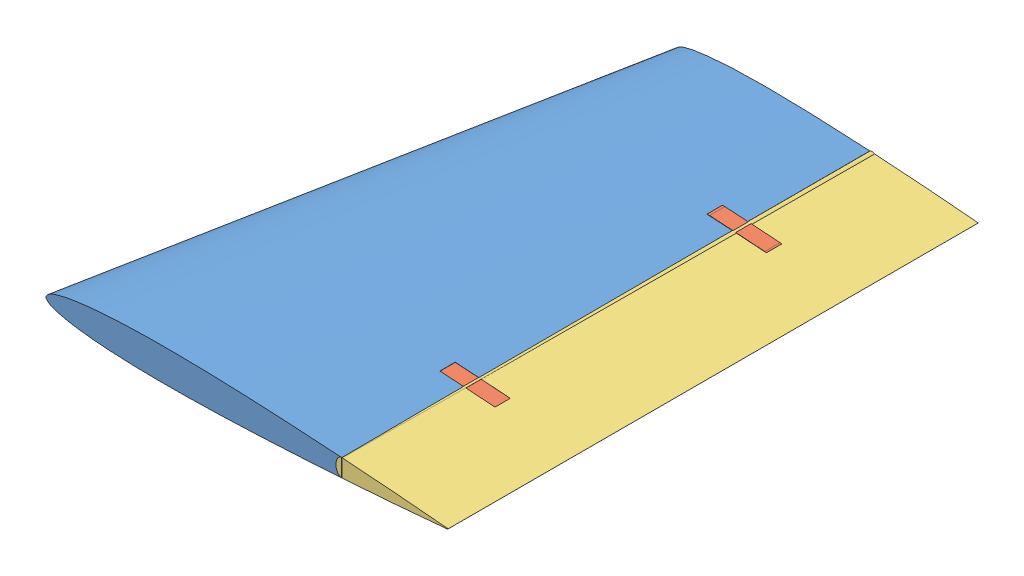
SolidWorks assembly Vertical tail, configuration Default. Lengths in mm.
Overall size (132.07 10.81 173.2).
4 component instances, 3 part files, 8 mates.
Components (placement in the parent):
- Vertical tail - rudder cut-1: Vertical tail - rudder cut [Default] at (-19.4442 96.0489 234.5051) size (131.87 10.81 173.19)
- Vertical tail - Rudder hinge-1: Vertical tail - Rudder hinge [Default] at (-19.4442 96.0645 272.3617) size (23.51 6.78 5.15)
- Vertical tail - Rudder hinge-2: Vertical tail - Rudder hinge [Default] at (-19.4442 96.0645 184.3617) size (23.51 6.78 5.15)
- Rudder-1: Rudder [Default] at (-19.4442 95.9836 234.5051) x (1 0.000643 0) z (0 0 1) size (36.62 5.96 173.2)
Mates (geometry in assembly coordinates):
- Coincident1: coincident anti-aligned: plane of Vertical tail - rudder cut-1 through (69.0558 106.0489 194.5051) normal (0 0 -1); plane of Vertical tail - Rudder hinge-1 through (39.2445 106.0645 194.5051) normal (0 0 1)
- Coincident4: coincident aligned: cylinder of Vertical tail - rudder cut-1 through (72.0558 96.0274 87.5051) axis (0 0 1) radius 1.5; circle of Vertical tail - Rudder hinge-1
- Concentric1: concentric aligned: cylinder of Vertical tail - rudder cut-1 through (72.0558 96.0274 87.5051) axis (0 0 1) radius 1.5; cylinder of Vertical tail - Rudder hinge-2 through (72.0558 96.0274 101.5051) axis (0 0 1) radius 1.5
- Coincident5: coincident anti-aligned: plane of Vertical tail - rudder cut-1 through (69.0558 106.0489 106.5051) normal (0 0 -1); plane of Vertical tail - Rudder hinge-2 through (39.2445 106.0645 106.5051) normal (0 0 1)
- Lock2: lock: unknown of Vertical tail - rudder cut-1; unknown of Vertical tail - Rudder hinge-2
- Lock3: lock: unknown of Vertical tail - rudder cut-1; unknown of Vertical tail - Rudder hinge-1
- Concentric2: concentric aligned: cylinder of Vertical tail - Rudder hinge-1 through (82.0558 96.0274 189.5051) axis (0 0 1) radius 1.5; cylinder of Rudder-1 through (82.0558 96.0274 83.5051) axis (0 0 1) radius 1.5
- Coincident6: coincident aligned: circle of Vertical tail - Rudder hinge-1; circle of Rudder-1
